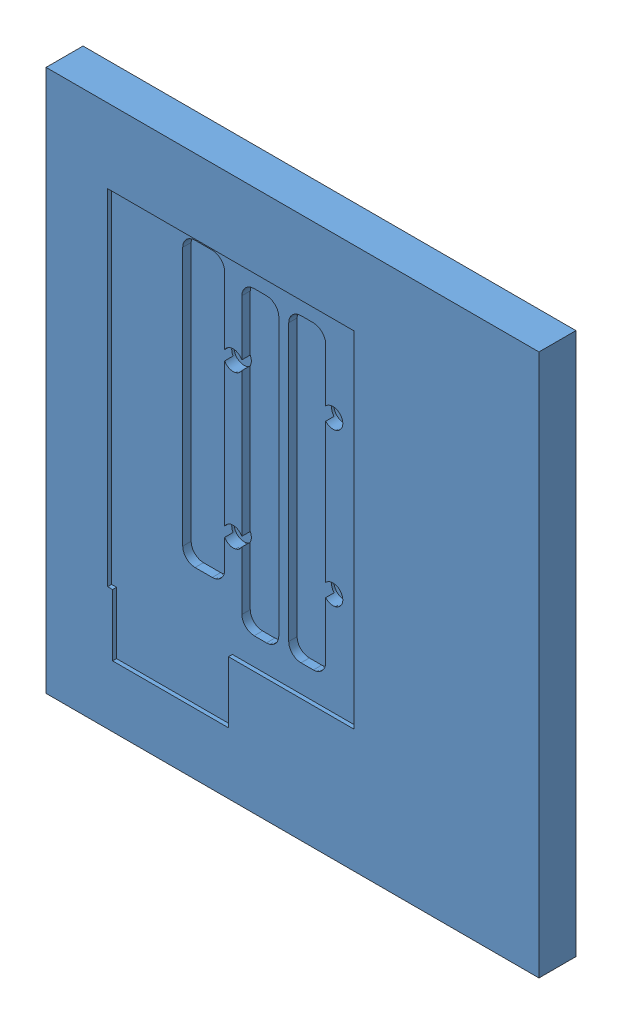
SolidWorks assembly Assemblage test support PCB, configuration Défaut. Lengths in mm.
Overall size (200 220 15).
83 component instances, 5 part files, 3 mates.
Components (placement in the parent):
- Support PCB BM13xx-16 01a-1: Support PCB BM13xx-16 01a [Défaut] at (-139.5414 -110.1302 -7.5) size (200 220 15)
- EKO_Miner_BM1366 PCBonly.step-1: EKO_Miner_BM1366 PCBonly.step [Défaut] at (-139.6914 -135.0045 5.9) x (0 1 0) z (0 0 1) size (148.4 99.75 4.88) (hidden)
  - SMTSO-M3-3ET.step-1: SMTSO-M3-3ET.step [Défaut] at (178 -115 1.25) x (0 0 -1) z (1 0 0) size (4.53 5.56 5.56)
    - 1.step-1: 1.step [Défaut] at origin size (4.53 5.56 5.56)
  - CP_EIA-7343-31_Kemet-D.step-1: CP_EIA-7343-31_Kemet-D.step [Défaut] at (138.6707 -104.934 -0.05) x (0 1 0) z (0 0 -1) size (7.3 4.3 3.1)
    - CP_EIA_7343_31_Kemet_D.step-1: CP_EIA_7343_31_Kemet_D.step [Défaut] at origin size (7.3 4.3 3.1)
  - C_1210_3225Metric.step-1: C_1210_3225Metric.step [Défaut] at (111.58 -61.5 -0.05) x (1 0 0) z (0 0 -1) size (3.2 2.5 2.5)
    - C_1210_3225Metric-0.step-1: C_1210_3225Metric-0.step [Défaut] at origin size (3.2 2.5 2.5)
  - C_1210_3225Metric.step-2: C_1210_3225Metric.step [Défaut] at (111.58 -68.104 -0.05) x (1 0 0) z (0 0 -1) size (3.2 2.5 2.5)
    - C_1210_3225Metric-0.step-1: C_1210_3225Metric-0.step [Défaut] at origin size (3.2 2.5 2.5)
  - CP_EIA-7343-31_Kemet-D.step-2: CP_EIA-7343-31_Kemet-D.step [Défaut] at (90.498 -84.106 -0.05) x (0 -1 0) z (0 0 -1) size (7.3 4.3 3.1)
    - CP_EIA_7343_31_Kemet_D.step-1: CP_EIA_7343_31_Kemet_D.step [Défaut] at origin size (7.3 4.3 3.1)
  - C_1210_3225Metric.step-3: C_1210_3225Metric.step [Défaut] at (208.98 -64.802 -0.05) x (1 0 0) z (0 0 -1) size (3.2 2.5 2.5)
    - C_1210_3225Metric-0.step-1: C_1210_3225Metric-0.step [Défaut] at origin size (3.2 2.5 2.5)
  - C_1210_3225Metric.step-4: C_1210_3225Metric.step [Défaut] at (144.0467 -61.5 -0.05) x (1 0 0) z (0 0 -1) size (3.2 2.5 2.5)
    - C_1210_3225Metric-0.step-1: C_1210_3225Metric-0.step [Défaut] at origin size (3.2 2.5 2.5)
  - C_1210_3225Metric.step-5: C_1210_3225Metric.step [Défaut] at (208.98 -58.2047 -0.05) x (1 0 0) z (0 0 -1) size (3.2 2.5 2.5)
    - C_1210_3225Metric-0.step-1: C_1210_3225Metric-0.step [Défaut] at origin size (3.2 2.5 2.5)
  - CP_EIA-7343-31_Kemet-D.step-3: CP_EIA-7343-31_Kemet-D.step [Défaut] at (154.9414 -84.106 -0.05) x (0 -1 0) z (0 0 -1) size (7.3 4.3 3.1)
    - CP_EIA_7343_31_Kemet_D.step-1: CP_EIA_7343_31_Kemet_D.step [Défaut] at origin size (7.3 4.3 3.1)
  - C_1210_3225Metric.step-6: C_1210_3225Metric.step [Défaut] at (144.0467 -64.802 -0.05) x (1 0 0) z (0 0 -1) size (3.2 2.5 2.5)
    - C_1210_3225Metric-0.step-1: C_1210_3225Metric-0.step [Défaut] at origin size (3.2 2.5 2.5)
  - CP_EIA-7343-31_Kemet-D.step-4: CP_EIA-7343-31_Kemet-D.step [Défaut] at (90.498 -104.934 -0.05) x (0 1 0) z (0 0 -1) size (7.3 4.3 3.1)
    - CP_EIA_7343_31_Kemet_D.step-1: CP_EIA_7343_31_Kemet_D.step [Défaut] at origin size (7.3 4.3 3.1)
  - C_1210_3225Metric.step-7: C_1210_3225Metric.step [Défaut] at (208.98 -61.5 -0.05) x (1 0 0) z (0 0 -1) size (3.2 2.5 2.5)
    - C_1210_3225Metric-0.step-1: C_1210_3225Metric-0.step [Défaut] at origin size (3.2 2.5 2.5)
  - CP_EIA-7343-31_Kemet-D.step-5: CP_EIA-7343-31_Kemet-D.step [Défaut] at (202.512 -104.934 -0.05) x (0 1 0) z (0 0 -1) size (7.3 4.3 3.1)
    - CP_EIA_7343_31_Kemet_D.step-1: CP_EIA_7343_31_Kemet_D.step [Défaut] at origin size (7.3 4.3 3.1)
  - SMTSO-M3-3ET.step-2: SMTSO-M3-3ET.step [Défaut] at (116 -74.5 1.25) x (0 0 -1) z (1 0 0) size (4.53 5.56 5.56)
    - 1.step-1: 1.step [Défaut] at origin size (4.53 5.56 5.56)
  - CP_EIA-7343-31_Kemet-D.step-6: CP_EIA-7343-31_Kemet-D.step [Défaut] at (186.51 -104.934 -0.05) x (0 1 0) z (0 0 -1) size (7.3 4.3 3.1)
    - CP_EIA_7343_31_Kemet_D.step-1: CP_EIA_7343_31_Kemet_D.step [Défaut] at origin size (7.3 4.3 3.1)
  - CP_EIA-7343-31_Kemet-D.step-7: CP_EIA-7343-31_Kemet-D.step [Défaut] at (154.6727 -104.934 -0.05) x (0 1 0) z (0 0 -1) size (7.3 4.3 3.1)
    - CP_EIA_7343_31_Kemet_D.step-1: CP_EIA_7343_31_Kemet_D.step [Défaut] at origin size (7.3 4.3 3.1)
  - C_1210_3225Metric.step-8: C_1210_3225Metric.step [Défaut] at (144.0467 -58.2047 -0.05) x (1 0 0) z (0 0 -1) size (3.2 2.5 2.5)
    - C_1210_3225Metric-0.step-1: C_1210_3225Metric-0.step [Défaut] at origin size (3.2 2.5 2.5)
  - CP_EIA-7343-31_Kemet-D.step-8: CP_EIA-7343-31_Kemet-D.step [Défaut] at (122.502 -104.934 -0.05) x (0 1 0) z (0 0 -1) size (7.3 4.3 3.1)
    - CP_EIA_7343_31_Kemet_D.step-1: CP_EIA_7343_31_Kemet_D.step [Défaut] at origin size (7.3 4.3 3.1)
  - CP_EIA-7343-31_Kemet-D.step-9: CP_EIA-7343-31_Kemet-D.step [Défaut] at (138.758 -84.106 -0.05) x (0 -1 0) z (0 0 -1) size (7.3 4.3 3.1)
    - CP_EIA_7343_31_Kemet_D.step-1: CP_EIA_7343_31_Kemet_D.step [Défaut] at origin size (7.3 4.3 3.1)
  - CP_EIA-7343-31_Kemet-D.step-10: CP_EIA-7343-31_Kemet-D.step [Défaut] at (168.0833 -58.8 -0.05) x (-1 0 0) z (0 0 -1) size (7.3 4.3 3.1)
    - CP_EIA_7343_31_Kemet_D.step-1: CP_EIA_7343_31_Kemet_D.step [Défaut] at origin size (7.3 4.3 3.1)
  - CP_EIA-7343-31_Kemet-D.step-11: CP_EIA-7343-31_Kemet-D.step [Défaut] at (103.15 -58.8 -0.05) x (-1 0 0) z (0 0 -1) size (7.3 4.3 3.1)
    - CP_EIA_7343_31_Kemet_D.step-1: CP_EIA_7343_31_Kemet_D.step [Défaut] at origin size (7.3 4.3 3.1)
  - C_1210_3225Metric.step-9: C_1210_3225Metric.step [Défaut] at (176.5133 -61.5 -0.05) x (1 0 0) z (0 0 -1) size (3.2 2.5 2.5)
    - C_1210_3225Metric-0.step-1: C_1210_3225Metric-0.step [Défaut] at origin size (3.2 2.5 2.5)
  - CP_EIA-7343-31_Kemet-D.step-12: CP_EIA-7343-31_Kemet-D.step [Défaut] at (171.0523 -84.106 -0.05) x (0 -1 0) z (0 0 -1) size (7.3 4.3 3.1)
    - CP_EIA_7343_31_Kemet_D.step-1: CP_EIA_7343_31_Kemet_D.step [Défaut] at origin size (7.3 4.3 3.1)
  - CP_EIA-7343-31_Kemet-D.step-13: CP_EIA-7343-31_Kemet-D.step [Défaut] at (200.55 -58.8 -0.05) x (-1 0 0) z (0 0 -1) size (7.3 4.3 3.1)
    - CP_EIA_7343_31_Kemet_D.step-1: CP_EIA_7343_31_Kemet_D.step [Défaut] at origin size (7.3 4.3 3.1)
  - CP_EIA-7343-31_Kemet-D.step-14: CP_EIA-7343-31_Kemet-D.step [Défaut] at (106.5 -104.934 -0.05) x (0 1 0) z (0 0 -1) size (7.3 4.3 3.1)
    - CP_EIA_7343_31_Kemet_D.step-1: CP_EIA_7343_31_Kemet_D.step [Défaut] at origin size (7.3 4.3 3.1)
  - C_1210_3225Metric.step-10: C_1210_3225Metric.step [Défaut] at (176.5133 -58.2047 -0.05) x (1 0 0) z (0 0 -1) size (3.2 2.5 2.5)
    - C_1210_3225Metric-0.step-1: C_1210_3225Metric-0.step [Défaut] at origin size (3.2 2.5 2.5)
  - C_1210_3225Metric.step-11: C_1210_3225Metric.step [Défaut] at (208.98 -68.104 -0.05) x (1 0 0) z (0 0 -1) size (3.2 2.5 2.5)
    - C_1210_3225Metric-0.step-1: C_1210_3225Metric-0.step [Défaut] at origin size (3.2 2.5 2.5)
  - CP_EIA-7343-31_Kemet-D.step-15: CP_EIA-7343-31_Kemet-D.step [Défaut] at (135.6167 -58.8 -0.05) x (-1 0 0) z (0 0 -1) size (7.3 4.3 3.1)
    - CP_EIA_7343_31_Kemet_D.step-1: CP_EIA_7343_31_Kemet_D.step [Défaut] at origin size (7.3 4.3 3.1)
  - CP_EIA-7343-31_Kemet-D.step-16: CP_EIA-7343-31_Kemet-D.step [Défaut] at (106.6089 -84.106 -0.05) x (0 -1 0) z (0 0 -1) size (7.3 4.3 3.1)
    - CP_EIA_7343_31_Kemet_D.step-1: CP_EIA_7343_31_Kemet_D.step [Défaut] at origin size (7.3 4.3 3.1)
  - SMTSO-M3-3ET.step-3: SMTSO-M3-3ET.step [Défaut] at (116 -115 1.25) x (0 0 -1) z (1 0 0) size (4.53 5.56 5.56)
    - 1.step-1: 1.step [Défaut] at origin size (4.53 5.56 5.56)
  - CP_EIA-7343-31_Kemet-D.step-17: CP_EIA-7343-31_Kemet-D.step [Défaut] at (122.756 -84.106 -0.05) x (0 -1 0) z (0 0 -1) size (7.3 4.3 3.1)
    - CP_EIA_7343_31_Kemet_D.step-1: CP_EIA_7343_31_Kemet_D.step [Défaut] at origin size (7.3 4.3 3.1)
  - SMTSO-M3-3ET.step-4: SMTSO-M3-3ET.step [Défaut] at (178 -74.5 1.25) x (0 0 -1) z (1 0 0) size (4.53 5.56 5.56)
    - 1.step-1: 1.step [Défaut] at origin size (4.53 5.56 5.56)
  - C_1210_3225Metric.step-12: C_1210_3225Metric.step [Défaut] at (111.58 -58.198 -0.05) x (1 0 0) z (0 0 -1) size (3.2 2.5 2.5)
    - C_1210_3225Metric-0.step-1: C_1210_3225Metric-0.step [Défaut] at origin size (3.2 2.5 2.5)
  - CP_EIA-7343-31_Kemet-D.step-18: CP_EIA-7343-31_Kemet-D.step [Défaut] at (187.2715 -84.086 -0.05) x (0 -1 0) z (0 0 -1) size (7.3 4.3 3.1)
    - CP_EIA_7343_31_Kemet_D.step-1: CP_EIA_7343_31_Kemet_D.step [Défaut] at origin size (7.3 4.3 3.1)
  - CP_EIA-7343-31_Kemet-D.step-19: CP_EIA-7343-31_Kemet-D.step [Défaut] at (203.274 -84.106 -0.05) x (0 -1 0) z (0 0 -1) size (7.3 4.3 3.1)
    - CP_EIA_7343_31_Kemet_D.step-1: CP_EIA_7343_31_Kemet_D.step [Défaut] at origin size (7.3 4.3 3.1)
  - C_1210_3225Metric.step-13: C_1210_3225Metric.step [Défaut] at (176.5133 -64.802 -0.05) x (1 0 0) z (0 0 -1) size (3.2 2.5 2.5)
    - C_1210_3225Metric-0.step-1: C_1210_3225Metric-0.step [Défaut] at origin size (3.2 2.5 2.5)
  - CP_EIA-7343-31_Kemet-D.step-20: CP_EIA-7343-31_Kemet-D.step [Défaut] at (170.508 -104.934 -0.05) x (0 1 0) z (0 0 -1) size (7.3 4.3 3.1)
    - CP_EIA_7343_31_Kemet_D.step-1: CP_EIA_7343_31_Kemet_D.step [Défaut] at origin size (7.3 4.3 3.1)
  - C_1210_3225Metric.step-14: C_1210_3225Metric.step [Défaut] at (176.5133 -68.104 -0.05) x (1 0 0) z (0 0 -1) size (3.2 2.5 2.5)
    - C_1210_3225Metric-0.step-1: C_1210_3225Metric-0.step [Défaut] at origin size (3.2 2.5 2.5)
  - C_1210_3225Metric.step-15: C_1210_3225Metric.step [Défaut] at (144.0467 -68.104 -0.05) x (1 0 0) z (0 0 -1) size (3.2 2.5 2.5)
    - C_1210_3225Metric-0.step-1: C_1210_3225Metric-0.step [Défaut] at origin size (3.2 2.5 2.5)
  - C_1210_3225Metric.step-16: C_1210_3225Metric.step [Défaut] at (111.58 -64.802 -0.05) x (1 0 0) z (0 0 -1) size (3.2 2.5 2.5)
    - C_1210_3225Metric-0.step-1: C_1210_3225Metric-0.step [Défaut] at origin size (3.2 2.5 2.5)
  - EKO_Miner_BM1366-13xx_16-01A PCBonly_PCB.step-1: EKO_Miner_BM1366-13xx_16-01A PCBonly_PCB.step [Défaut] at origin size (148.4 99.75 1.6)
Mates (geometry in assembly coordinates):
- Coïncidente1: coincident anti-aligned: plane of Support PCB BM13xx-16 01a-1 through (-14.6914 -60.2145 5.9) normal (-1 0 0); plane of EKO_Miner_BM1366 PCBonly.step-1/EKO_Miner_BM1366-13xx_16-01A PCBonly_PCB.step-1 through (-14.6914 79.7455 5.9) normal (1 0 0)
- Coïncidente2: coincident anti-aligned: plane of Support PCB BM13xx-16 01a-1 through (-114.5414 79.7455 5.9) normal (0 -1 0); plane of EKO_Miner_BM1366 PCBonly.step-1/EKO_Miner_BM1366-13xx_16-01A PCBonly_PCB.step-1 through (-114.4414 79.7455 5.9) normal (0 1 0)
- Coïncidente3: coincident aligned: plane of Support PCB BM13xx-16 01a-1 through (-139.5414 -110.1302 7.5) normal (0 0 1); plane of EKO_Miner_BM1366 PCBonly.step-1/EKO_Miner_BM1366-13xx_16-01A PCBonly_PCB.step-1 through (-67.2886 0.5674 7.5) normal (0 0 1)
